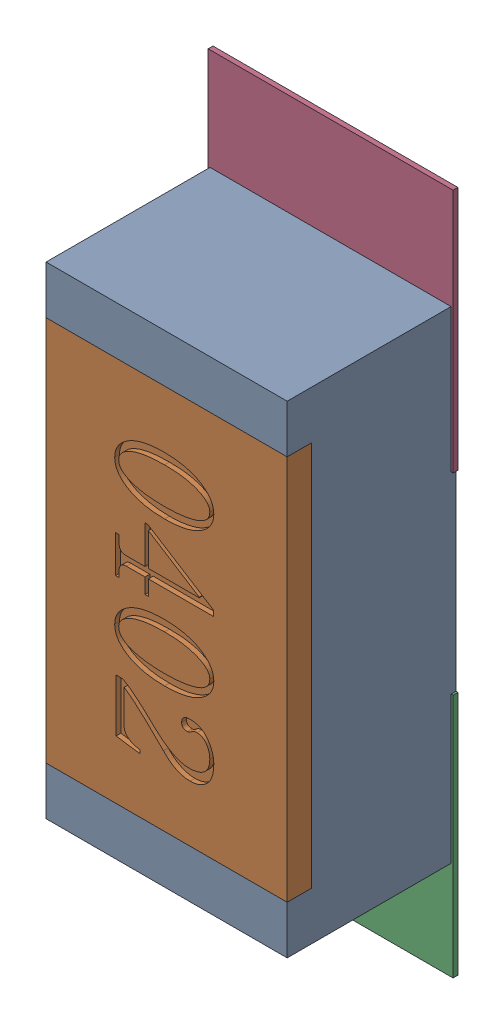
SolidWorks assembly R60, configuration Défaut. Lengths in mm.
Overall size (0.51 1.42 0.35).
5 component instances, 2 part files, 0 mates.
Components (placement in the parent):
- R0402-1: R0402 [Défaut] at (33.4135 -32.3342 0) x (0 -1 0) z (0 0 1) size (1 0.5 0.35)
- 6504207776-1: 6504207776 [Défaut] at (33.4136 -32.7842 0) size (0.51 0.51 0.01)
  - Extruded-1: Extruded [Défaut] at origin size (0.51 0.51 0.01)
- 6504207776-2: 6504207776 [Défaut] at (33.4136 -31.8771 0) size (0.51 0.51 0.01)
  - Extruded-1: Extruded [Défaut] at origin size (0.51 0.51 0.01)
